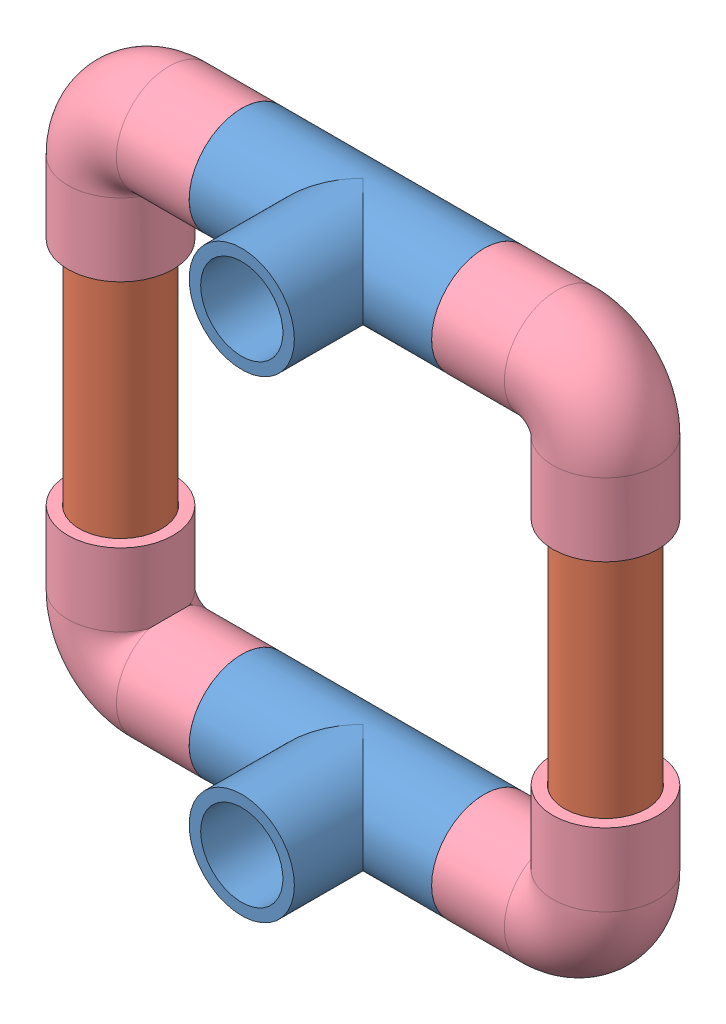
SolidWorks assembly SCOUT CUBE SATS BASE, configuration Default. Lengths in mm.
Overall size (155.55 151.41 46.52).
12 component instances, 4 part files, 21 mates.
Components (placement in the parent):
- 1-2 PVC TEE-2: 1-2 PVC TEE [4880K41] at (-59.0895 -22.7694 164.8713) x (1 0 0) z (0 -1 0) size (63.5 45.53 27.56)
- 1-2 PVC TEE-5: 1-2 PVC TEE [4880K41] at (-59.0895 101.0801 164.8713) x (1 0 0) z (0 -1 0) size (63.5 45.53 27.56)
- 1-2 PVC PIPE 10CM-1: 1-2 PVC PIPE 10CM [48925K91] at (-122.5895 38.3801 164.8713) x (1 0 0) z (0 -1 0) size (21.34 21.34 100)
- 1-2 PVC PIPE 10CM-2: 1-2 PVC PIPE 10CM [48925K91] at (4.4105 38.3801 164.8713) x (0.837169 0 0.546944) z (0 1 0) size (21.34 21.34 100)
- 1-2 PVC PIPE 3CM-1: 1-2 PVC PIPE 3CM [48925K91] at (-90.8395 -22.7694 164.8713) x (0 0 1) z (-1 0 0) size (21.34 21.34 38.1)
- 1-2 PVC PIPE 3CM-2: 1-2 PVC PIPE 3CM [48925K91] at (-27.3395 -22.7694 164.8713) x (0 0 1) z (-1 0 0) size (21.34 21.34 38.1)
- 1-2 PVC PIPE 3CM-3: 1-2 PVC PIPE 3CM [48925K91] at (-90.8395 101.0801 164.8713) x (0 0 1) z (-1 0 0) size (21.34 21.34 38.1)
- 1-2 PVC PIPE 3CM-4: 1-2 PVC PIPE 3CM [48925K91] at (-27.3395 101.0801 164.8713) x (0 0 1) z (-1 0 0) size (21.34 21.34 38.1)
- 1-2 PVC ELBOW-1: 1-2 PVC ELBOW [4880K21] at (-122.5895 -22.7694 164.8713) x (-1 0 0) z (0 0 -1) size (45.53 45.53 27.56)
- 1-2 PVC ELBOW-2: 1-2 PVC ELBOW [4880K21] at (-122.5895 101.0801 164.8713) x (-1 0 0) z (0 0 1) size (45.53 45.53 27.56)
- 1-2 PVC ELBOW-3: 1-2 PVC ELBOW [4880K21] at (4.4105 -22.7694 164.8713) size (45.53 45.53 27.56)
- 1-2 PVC ELBOW-4: 1-2 PVC ELBOW [4880K21] at (4.4105 101.0801 164.8713) x (0 1 0) z (0 0 1) size (45.53 45.53 27.56)
Mates (geometry in assembly coordinates):
- Coincident2: coincident anti-aligned: plane of 1-2 PVC TEE-2 through (-71.7895 -22.7694 164.8713) normal (-1 0 0); plane of 1-2 PVC PIPE 3CM-1 through (-71.7895 -22.7694 164.8713) normal (1 0 0)
- Concentric2: concentric anti-aligned: cylinder of 1-2 PVC TEE-2 through (-46.3895 -22.7694 164.8713) axis (-1 0 0) radius 13.7795; cylinder of 1-2 PVC PIPE 3CM-1 through (-109.8895 -22.7694 164.8713) axis (1 0 0) radius 10.668
- Coincident3: coincident anti-aligned: plane of 1-2 PVC TEE-2 through (-46.3895 -22.7694 164.8713) normal (1 0 0); plane of 1-2 PVC PIPE 3CM-2 through (-46.3895 -22.7694 164.8713) normal (-1 0 0)
- Concentric3: concentric anti-aligned: cone of 1-2 PVC TEE-2 through (-27.3395 -22.7694 164.8713) axis (-1 0 0); cylinder of 1-2 PVC PIPE 3CM-2 through (-46.3895 -22.7694 164.8713) axis (1 0 0) radius 10.668
- Coincident6: coincident anti-aligned: plane of 1-2 PVC TEE-5 through (-71.7895 101.0801 164.8713) normal (-1 0 0); plane of 1-2 PVC PIPE 3CM-3 through (-71.7895 101.0801 164.8713) normal (1 0 0)
- Concentric6: concentric anti-aligned: cylinder of 1-2 PVC TEE-5 through (-46.3895 101.0801 164.8713) axis (-1 0 0) radius 13.7795; cylinder of 1-2 PVC PIPE 3CM-3 through (-109.8895 101.0801 164.8713) axis (1 0 0) radius 10.668
- Coincident7: coincident anti-aligned: plane of 1-2 PVC TEE-5 through (-46.3895 101.0801 164.8713) normal (1 0 0); plane of 1-2 PVC PIPE 3CM-4 through (-46.3895 101.0801 164.8713) normal (-1 0 0)
- Concentric7: concentric anti-aligned: cone of 1-2 PVC TEE-5 through (-27.3395 101.0801 164.8713) axis (-1 0 0); cylinder of 1-2 PVC PIPE 3CM-4 through (-46.3895 101.0801 164.8713) axis (1 0 0) radius 10.668
- Coincident13: coincident aligned: plane of 1-2 PVC TEE-2 through (-45.31 -22.7694 196.6213) normal (0 0 1); plane of 1-2 PVC TEE-5 through (-45.31 101.0801 196.6213) normal (0 0 1)
- Coincident14: coincident anti-aligned: plane of 1-2 PVC TEE-5 through (-27.3395 101.0801 151.0918) normal (1 0 0); plane of 1-2 PVC ELBOW-4 through (-27.3395 114.8596 164.8713) normal (-1 0 0)
- Concentric8: concentric anti-aligned: cylinder of 1-2 PVC TEE-5 through (-46.3895 101.0801 164.8713) axis (-1 0 0) radius 13.7795; cylinder of 1-2 PVC ELBOW-4 through (4.4105 101.0801 164.8713) axis (1 0 0) radius 13.7795
- Concentric9: concentric aligned: cylinder of 1-2 PVC PIPE 10CM-2 through (4.4105 88.3801 164.8713) axis (0 -1 0) radius 10.668; cylinder of 1-2 PVC ELBOW-4 through (4.4105 69.3301 164.8713) axis (0 -1 0) radius 13.7795
- Concentric10: concentric aligned: cylinder of 1-2 PVC PIPE 10CM-2 through (4.4105 88.3801 164.8713) axis (0 -1 0) radius 10.668; cylinder of 1-2 PVC ELBOW-3 through (4.4105 -22.7694 164.8713) axis (0 -1 0) radius 13.7795
- Concentric11: concentric aligned: cylinder of 1-2 PVC TEE-2 through (-46.3895 -22.7694 164.8713) axis (-1 0 0) radius 13.7795; cylinder of 1-2 PVC ELBOW-3 through (-27.3395 -22.7694 164.8713) axis (-1 0 0) radius 13.7795
- Coincident15: coincident anti-aligned: plane of 1-2 PVC TEE-2 through (-27.3395 -22.7694 151.0918) normal (1 0 0); plane of 1-2 PVC ELBOW-3 through (-27.3395 -36.5489 164.8713) normal (-1 0 0)
- Concentric12: concentric anti-aligned: cylinder of 1-2 PVC PIPE 10CM-1 through (-122.5895 -11.6199 164.8713) axis (0 1 0) radius 10.668; cylinder of 1-2 PVC ELBOW-1 through (-122.5895 -39.4701 164.8713) axis (0 -1 0) radius 13.7795
- Concentric14: concentric aligned: cylinder of 1-2 PVC PIPE 10CM-1 through (-122.5895 -11.6199 164.8713) axis (0 1 0) radius 10.668; cylinder of 1-2 PVC ELBOW-2 through (-122.5895 101.0801 164.8713) axis (0 1 0) radius 13.7795
- Concentric15: concentric anti-aligned: cylinder of 1-2 PVC TEE-5 through (-46.3895 101.0801 164.8713) axis (-1 0 0) radius 13.7795; cylinder of 1-2 PVC ELBOW-2 through (-90.8395 101.0801 164.8713) axis (1 0 0) radius 13.7795
- Coincident16: coincident anti-aligned: plane of 1-2 PVC TEE-5 through (-90.8395 101.0801 151.0918) normal (-1 0 0); plane of 1-2 PVC ELBOW-2 through (-90.8395 114.8596 164.8713) normal (1 0 0)
- Parallel1: parallel anti-aligned: plane of 1-2 PVC TEE-2 through (-90.8395 -22.7694 151.0918) normal (-1 0 0); plane of 1-2 PVC ELBOW-1 through (-90.8395 -36.5489 164.8713) normal (1 0 0)
- Concentric16: concentric anti-aligned: cylinder of 1-2 PVC TEE-2 through (-46.3895 -22.7694 164.8713) axis (-1 0 0) radius 13.7795; cylinder of 1-2 PVC ELBOW-1 through (-90.8395 -22.7694 164.8713) axis (1 0 0) radius 13.7795
